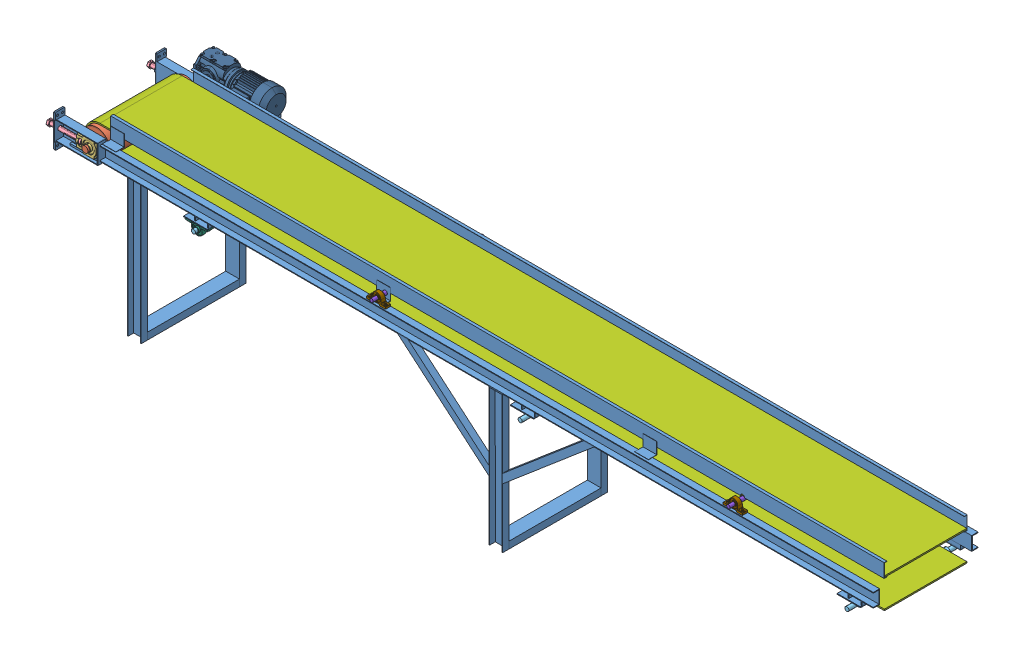
SolidWorks assembly Assembly of conveyor, configuration Default. Lengths in mm.
Overall size (6019.32 1249.64 1082.69).
22 component instances, 12 part files, 36 mates.
Components (placement in the parent):
- C-channel -b-up-2: C-channel -b-up [Default<As Machined>] at (4036.4781 3775.6231 338.4141) x (0.000207 -1 -0.000382) z (-1 -0.000206 -0.000489) size (1248 1076.8 6547.03)
- roller-belt-Motor-up-1: roller-belt-Motor-up [Default] at (7146.6561 3780.3929 4.9357) x (0.000489 0.000382 -1) z (1 0 0.000489) size (812 200 200)
- roller-belt-Motor-up -lower-1: roller-belt-Motor-up -lower [Default] at (956.6422 3775.1154 1.9089) x (0.000489 0.000382 -1) z (1 0 0.000489) size (847.54 200 200)
- Uct 209-up-1: Uct 209-up [Default] at (956.4633 3774.9756 367.9088) x (1 0.000206 0.000489) z (-0.000489 -0.000382 1) size (144 117 54.7)
- Extender-screw-up-1: Extender-screw-up [Default] at (892.9633 3774.9625 367.8777) x (0.000489 0 -1) z (-1 -0.000206 -0.000489) size (46.02 42.15 250)
- Bearing-b_P209_45-up-1: Bearing-b_P209_45-up [Default] at (7146.4904 3726.2546 366.915) x (1 0.000206 0.000489) z (-0.000489 -0.000382 1) size (190 108 62)
- upper-roller-inside-up-1: upper-roller-inside-up [Default] at (6502.8061 3649.373 4.571) x (1 0 0.000489) z (-0.000489 -0.000382 1) size (50 50 810)
- UCP206-3: UCP206 [Varsayılan] at (1742.6291 3648.2519 365.7446) x (-0.000489 -0.000382 1) z (0.000207 -1 -0.000382) size (62 165 84.42)
- Bearing-b_P209_45-up-2: Bearing-b_P209_45-up [Default] at (7146.8442 3726.5311 -357.0849) x (-1 -0.000206 -0.000489) z (0.000489 0.000382 -1) size (190 108 62)
- UCP206-6: UCP206 [Varsayılan] at (1742.9844 3648.5294 -361.2553) x (-0.000489 -0.000382 1) z (0.000207 -1 -0.000382) size (62 165 84.42)
- Uct 209-up-2: Uct 209-up [Default] at (956.821 3775.2551 -364.0911) x (1 0.000206 0.000489) z (0.000489 0.000382 -1) size (144 117 54.7)
- Extender-screw-up-2: Extender-screw-up [Default] at (893.321 3775.242 -364.1221) x (0.000489 0.000764 -1) z (-1 -0.000206 -0.000489) size (46.02 42.15 250)
- upper-roller-inside-up-2: upper-roller-inside-up [Default] at (4122.8064 3648.8818 3.4078) x (1 0 0.000489) z (-0.000489 -0.000382 1) size (50 50 810)
- upper-roller-inside-up-3: upper-roller-inside-up [Default] at (1742.8067 3648.3906 2.2446) x (1 0 0.000489) z (-0.000489 -0.000382 1) size (50 50 810)
- Belt^Assembly of conveyor-1: Belt^Assembly of conveyor [Default] at (4036.6418 3775.751 3.4142) x (-0.000207 1 0.000382) z (0.000489 0.000382 -1) size (224 6410.02 600) (virtual)
- roller-upper-2: roller-upper [Default] at (5639.6653 3862.5818 4.2307) x (1 0 0.000489) z (-0.000489 -0.000382 1) size (29 29 810)
- UCP-205-1: UCP-205 [Default] at (5639.4923 3862.4467 358.2306) x (0.000489 0.000382 -1) z (1 0 0.000489) size (38.7 70 140)
- UCP-205-2: UCP-205 [Default] at (5639.8383 3862.717 -349.7693) x (0.000489 0.000382 -1) z (1 0.000206 0.000489) size (38.7 70 140)
- UCP-205-3: UCP-205 [Default] at (3039.8387 3862.1804 -351.04) x (0.000489 0.000382 -1) z (1 0.000206 0.000489) size (38.7 70 140)
- UCP-205-4: UCP-205 [Default] at (3039.4927 3861.9101 356.9599) x (0.000489 0.000382 -1) z (1 0 0.000489) size (38.7 70 140)
- roller-upper-3: roller-upper [Default] at (3039.6657 3862.0453 2.9599) x (1 0 0.000489) z (-0.000489 -0.000382 1) size (29 29 810)
- Gear_motor-b-up-1: Gear_motor-b-up [Default] at (1091.3076 3642.3291 -485.0761) x (1 0.000206 0.000489) z (-0.000489 -0.000382 1) size (516.61 233.87 272.3)
Mates (geometry in assembly coordinates):
- Coincident1: coincident: plane of C-channel -b-up-2 through (4036.6418 3775.751 3.4142) normal (0.000489 0.000382 -1)
- Concentric1: concentric anti-aligned: cylinder of C-channel -b-up-2 through (956.8005 3775.2391 -322.0911) axis (0.000489 0.000382 -1) radius 25; cylinder of roller-belt-Motor-up -lower-1 through (956.8425 3775.2719 -408.0911) axis (-0.000489 -0.000382 1) radius 22.5
- Width1: width anti-aligned: plane of C-channel -b-up-2 through (1036.7956 3825.2598 -333.0329) normal (-0.000489 -0.000382 1); plane of C-channel -b-up-2 through (1036.4681 3825.004 336.967) normal (0.000489 0.000382 -1); plane of roller-belt-Motor-up -lower-1 through (956.801 3775.2395 -323.0911) normal (0.000489 0.000382 -1); plane of roller-belt-Motor-up -lower-1 through (956.4834 3774.9913 326.9088) normal (-0.000489 -0.000382 1)
- Concentric2: concentric anti-aligned: cylinder of roller-belt-Motor-up -lower-1 through (956.8425 3775.2719 -408.0911) axis (-0.000489 -0.000382 1) radius 22.5; cylinder of Uct 209-up-1 through (956.4486 3774.9641 398.1088) axis (0.000489 0.000382 -1) radius 22.5
- Coincident2: coincident anti-aligned: plane of C-channel -b-up-2 through (810.446 3839.9425 375.8622) normal (-0.000489 -0.000382 1); plane of Uct 209-up-1 through (1005.9473 3833.4828 375.9553) normal (0.000489 0.000382 -1)
- Parallel1: parallel anti-aligned: plane of C-channel -b-up-2 through (810.4487 3826.9425 375.8573) normal (0.000207 -1 -0.000382); plane of Uct 209-up-1 through (1005.9567 3825.9889 359.9524) normal (-0.000207 1 0.000382)
- Concentric3: concentric aligned: cylinder of Uct 209-up-1 through (869.4634 3774.9577 367.8663) axis (1 0.000206 0.000489) radius 14.5; cylinder of Extender-screw-up-1 through (652.4634 3774.9129 367.7602) axis (1 0.000206 0.000489) radius 14.5
- Coincident3: coincident anti-aligned: plane of Uct 209-up-1 through (885.4696 3793.2991 347.3811) normal (1 0.000206 0.000489); plane of Extender-screw-up-1 through (885.4633 3774.961 367.8741) normal (-1 -0.000206 -0.000489)
- Coincident4: coincident anti-aligned: plane of C-channel -b-up-2 through (6936.5192 3726.2216 339.8124) normal (-0.000207 1 0.000382); plane of Bearing-b_P209_45-up-1 through (7051.4772 3726.2247 393.8686) normal (0.000207 -1 -0.000382)
- Coincident5: coincident aligned: plane of C-channel -b-up-2 through (4036.4781 3775.6231 338.4141) normal (0.000489 0.000382 -1); plane of Bearing-b_P209_45-up-1 through (7146.5036 3726.265 339.915) normal (0.000489 0.000382 -1)
- Concentric4: concentric aligned: cylinder of Bearing-b_P209_45-up-1 through (7146.5193 3780.286 284.9356) axis (-0.000489 -0.000382 1) radius 22.5; cylinder of roller-belt-Motor-up-1 through (7146.8545 3780.5479 -401.0642) axis (-0.000489 -0.000382 1) radius 22.5
- Coincident6: coincident anti-aligned: plane of C-channel -b-up-2 through (-723.5039 3690.6538 336.0556) normal (0.000207 -1 -0.000382); plane of UCP206-3 through (1710.6085 3691.1361 389.7453) normal (-0.000207 1 0.000382)
- Width4: width aligned: plane of C-channel -b-up-2 through (1657.6337 3691.1448 338.2194) normal (-1 -0.000206 -0.000489); plane of C-channel -b-up-2 through (1827.6337 3691.1799 338.3025) normal (1 0.000206 0.000489); plane of UCP206-3 through (1660.11 3691.1268 386.7206) normal (-1 -0.000206 -0.000489); plane of UCP206-3 through (1825.1305 3691.1769 344.8013) normal (1 0.000206 0.000489)
- Width5: width anti-aligned: plane of UCP206-3 through (1777.632 3691.1682 341.7781) normal (0.000489 0.000382 -1); plane of UCP206-3 through (1822.1085 3691.1591 389.7998) normal (-0.000489 -0.000382 1); plane of C-channel -b-up-2 through (1827.6068 3691.1589 393.3025) normal (-0.000489 -0.000382 1); plane of C-channel -b-up-2 through (1827.6337 3691.1799 338.3025) normal (0.000489 0.000382 -1)
- Coincident8: coincident anti-aligned: plane of C-channel -b-up-2 through (1656.4957 3691.145 337.2188) normal (0.000207 -1 -0.000382); plane of UCP206-1 through (4090.6082 3691.6273 390.9085) normal (-0.000207 1 0.000382)
- Width6: width anti-aligned: plane of UCP206-1 through (4040.1097 3691.618 387.8838) normal (-1 -0.000206 -0.000489); plane of UCP206-1 through (4205.1302 3691.6681 345.9645) normal (1 0.000206 0.000489); plane of C-channel -b-up-2 through (4207.6333 3691.6711 339.4657) normal (1 0.000206 0.000489); plane of C-channel -b-up-2 through (4037.6334 3691.636 339.3826) normal (-1 -0.000206 -0.000489)
- Width7: width anti-aligned: plane of UCP206-1 through (4087.6082 3691.6266 390.907) normal (-0.000489 -0.000382 1); plane of UCP206-1 through (4043.1316 3691.6358 342.8853) normal (0.000489 0.000382 -1); plane of C-channel -b-up-2 through (4207.6333 3691.6711 339.4657) normal (0.000489 0.000382 -1); plane of C-channel -b-up-2 through (4207.6065 3691.6501 394.4657) normal (-0.000489 -0.000382 1)
- Coincident9: coincident anti-aligned: plane of C-channel -b-up-2 through (4036.4954 3691.6361 338.3821) normal (0.000207 -1 -0.000382); plane of UCP206-2 through (6470.6078 3692.1184 392.0717) normal (-0.000207 1 0.000382)
- Width8: width anti-aligned: plane of C-channel -b-up-2 through (6587.6061 3692.1412 395.6289) normal (-0.000489 -0.000382 1); plane of C-channel -b-up-2 through (6587.633 3692.1622 340.6289) normal (0.000489 0.000382 -1); plane of UCP206-2 through (6423.1313 3692.127 344.0485) normal (0.000489 0.000382 -1); plane of UCP206-2 through (6467.6078 3692.1178 392.0702) normal (-0.000489 -0.000382 1)
- Width9: width anti-aligned: plane of C-channel -b-up-2 through (6417.633 3692.1272 340.5458) normal (-1 -0.000206 -0.000489); plane of C-channel -b-up-2 through (6587.633 3692.1622 340.6289) normal (1 0.000206 0.000489); plane of UCP206-2 through (6585.1298 3692.1592 347.1277) normal (1 0.000206 0.000489); plane of UCP206-2 through (6420.1093 3692.1092 389.047) normal (-1 -0.000206 -0.000489)
- Concentric5: concentric anti-aligned: cylinder of upper-roller-inside-up-1 through (6502.6082 3649.2184 409.571) axis (0.000489 0.000382 -1) radius 15; cylinder of UCP206-2 through (6502.6358 3649.24 352.933) axis (-0.000489 -0.000382 1) radius 15
- Concentric6: concentric anti-aligned: cylinder of UCP206-1 through (4122.6362 3648.7488 351.7698) axis (-0.000489 -0.000382 1) radius 15; cylinder of upper-roller-inside-up-2 through (4122.6085 3648.7272 408.4078) axis (0.000489 0.000382 -1) radius 15
- Concentric7: concentric anti-aligned: cylinder of UCP206-3 through (1742.6365 3648.2576 350.6066) axis (-0.000489 -0.000382 1) radius 15; cylinder of upper-roller-inside-up-3 through (1742.6088 3648.236 407.2446) axis (0.000489 0.000382 -1) radius 15
- Width12: width anti-aligned: plane of upper-roller-inside-up-3 through (1742.6088 3648.236 407.2446) normal (-0.000489 -0.000382 1); plane of upper-roller-inside-up-3 through (1743.0046 3648.5453 -402.7553) normal (0.000489 0.000382 -1); plane of C-channel -b-up-2 through (1036.4681 3825.004 336.967) normal (0.000489 0.000382 -1); plane of C-channel -b-up-2 through (1036.7956 3825.2598 -333.0329) normal (-0.000489 -0.000382 1)
- InPlace1: in place: plane of ? through (4036.6525 3723.6228 3.3943) normal (0.000489 0.000382 -1); plane of ? through (4036.6525 3723.6228 3.3943) normal (0.000489 0.000382 -1); moOrthogonalPlaneRef_w of ? through (4036.6525 3723.6228 3.3943) normal (0.000489 0.000382 -1); plane of ? through (4036.6525 3723.6228 3.3943) normal (1 0.000206 0.000489); plane of ? through (4036.6525 3723.6228 3.3943) normal (0.000489 0.000382 -1); plane of ? through (4036.6525 3723.6228 3.3943) normal (-0.000207 1 0.000382); plane of C-channel -b-up-2 through (4036.6418 3775.751 3.4142) normal (0.000489 0.000382 -1); unknown of Belt^Assembly of conveyor-1
- Coincident13: coincident aligned: plane of C-channel -b-up-2; plane of Belt^Assembly of conveyor-1
- Coincident14: coincident aligned: moOrthogonalPlaneRef_w of C-channel -b-up-2; plane of Belt^Assembly of conveyor-1 through (4036.6418 3775.751 3.4142) normal (1 0.000206 0.000489)
- Coincident15: coincident anti-aligned: moOrthogonalPlaneRef_w of C-channel -b-up-2; plane of Belt^Assembly of conveyor-1 through (4036.6418 3775.751 3.4142) normal (-0.000207 1 0.000382)
- Concentric11: concentric anti-aligned: cylinder of roller-upper-2 through (5639.4674 3862.4272 409.2306) axis (0.000489 0.000382 -1) radius 12.5; cylinder of UCP-205-1 through (5639.4853 3862.4412 372.5306) axis (-0.000489 -0.000382 1) radius 12.5
- Coincident24: coincident aligned: plane of C-channel -b-up-2 through (1036.4681 3825.004 336.967) normal (0.000489 0.000382 -1); plane of UCP-205-1 through (5571.1016 3838.7539 339.1881) normal (0.000489 0.000382 -1)
- Concentric12: concentric aligned: cylinder of roller-upper-2 through (5639.8632 3862.7365 -400.7693) axis (-0.000489 -0.000382 1) radius 12.5; cylinder of UCP-205-2 through (5639.8313 3862.7115 -335.4693) axis (-0.000489 -0.000382 1) radius 12.5
- Coincident25: coincident anti-aligned: plane of C-channel -b-up-2 through (1036.7956 3825.2598 -333.0329) normal (-0.000207 1 0.000382); plane of UCP-205-2 through (5709.8551 3826.2387 -368.749) normal (0.000207 -1 -0.000382)
- Coincident26: coincident aligned: plane of C-channel -b-up-2 through (1036.7956 3825.2598 -333.0329) normal (-0.000489 -0.000382 1); plane of UCP-205-2 through (5571.4339 3838.9956 -330.8117) normal (-0.000489 -0.000382 1)
- Coincident28: coincident anti-aligned: plane of roller-belt-Motor-up -lower-1 through (956.8425 3775.2719 -408.0911) normal (0.000489 0.000382 -1); plane of Gear_motor-b-up-1 through (972.9459 3759.1753 -408.0893) normal (-0.000489 -0.000382 1)
- Concentric14: concentric anti-aligned: circle of roller-belt-Motor-up -lower-1; cylinder of Gear_motor-b-up-1 through (956.8767 3775.2987 -478.0911) axis (-0.000489 -0.000382 1) radius 17.5
- Parallel2: parallel aligned: plane of C-channel -b-up-2 through (1036.8162 3725.2598 -333.0711) normal (0.000207 -1 -0.000382); plane of Gear_motor-b-up-1 through (1248.8044 3664.8321 -669.7906) normal (0.000207 -1 -0.000382)
